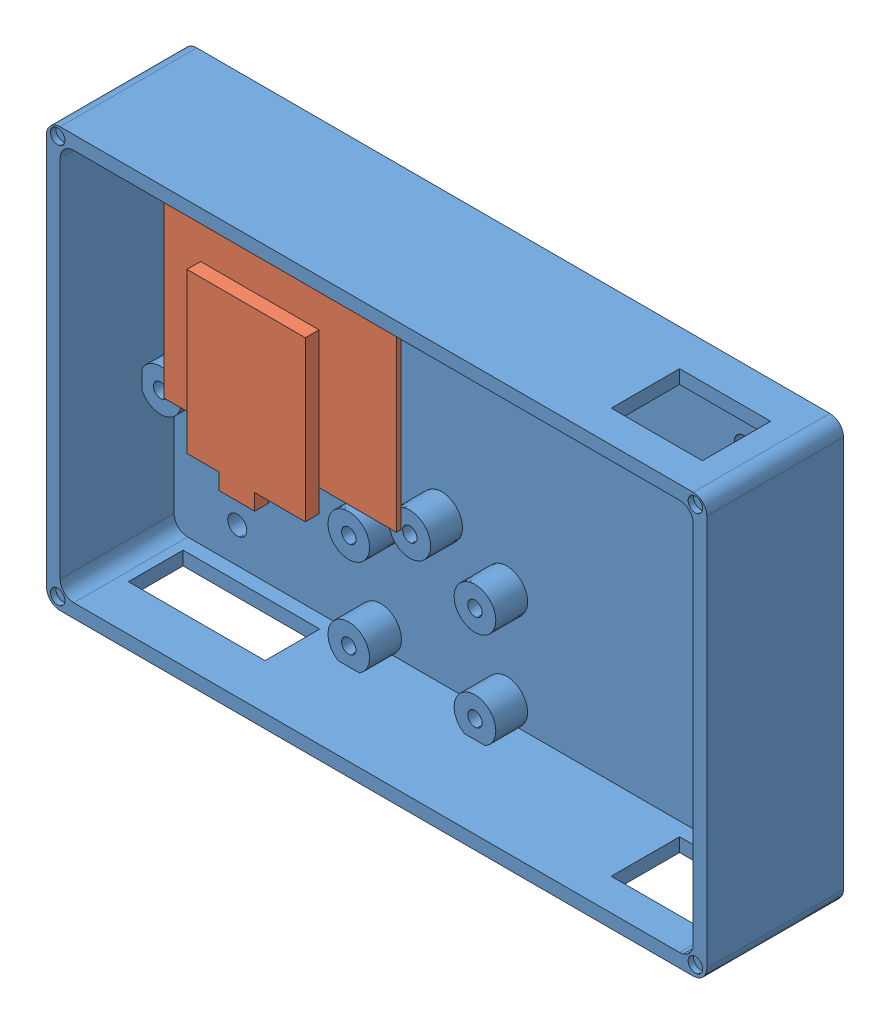
SolidWorks assembly Ensamblaje1, configuration Predeterminado. Lengths in mm.
Overall size (145 92 30).
2 component instances, 2 part files, 1 mates.
Components (placement in the parent):
- Carcasa-1: Carcasa [Predeterminado] at (-73.6727 46.807 110) size (145 92 30)
- PCB-1: PCB [Predeterminado] at (-12.8276 40.6154 122) x (0 -1 0) z (0 0 1) size (59.54 51 4)
Mates (geometry in assembly coordinates):
- Coincidente1: coincident anti-aligned: plane of Carcasa-1 through (-73.6727 46.807 122) normal (0 0 1); plane of PCB-1 through (-12.8276 40.6154 122) normal (0 0 -1)
